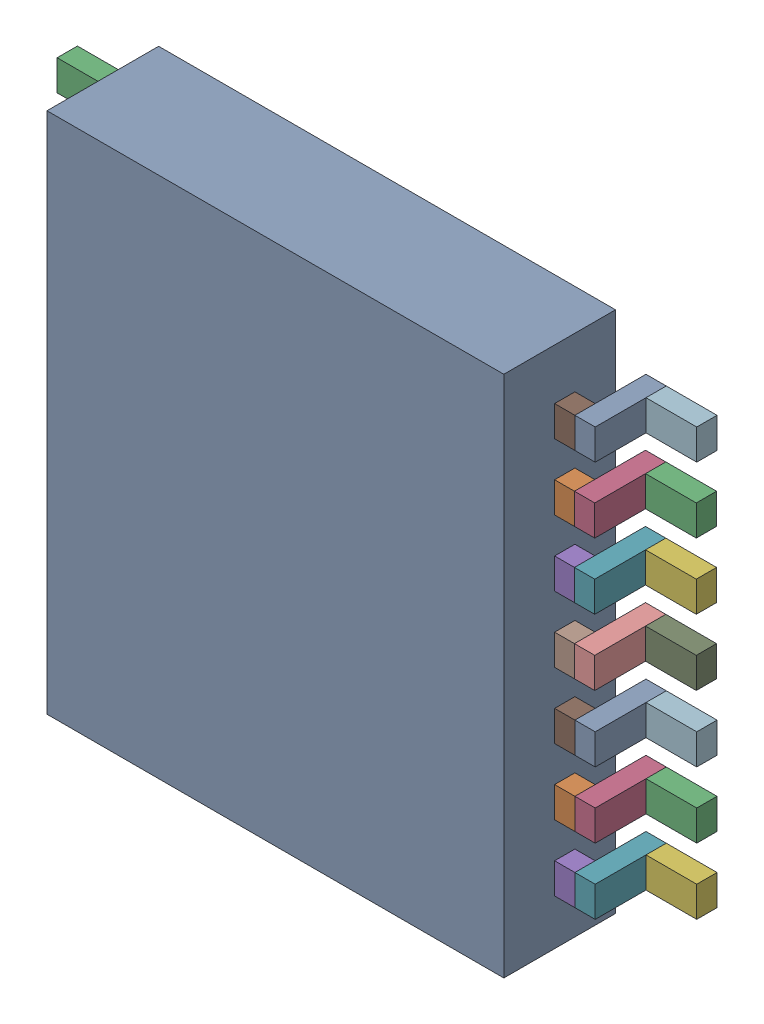
SolidWorks assembly U8, configuration Default. Lengths in mm.
Overall size (6.3 5.15 1.2).
86 component instances, 4 part files, 0 mates.
Components (placement in the parent):
- 859196720-1: 859196720 [Default] at (110.55 36.725 0.1) size (4.5 5.15 1.1)
  - Extruded_27-1: Extruded_27 [Default] at origin size (4.5 5.15 1.1)
- 836750064-1: 836750064 [Default] at (108 38.65 0) size (0.2 0.3 0.7)
  - Extruded_24-1: Extruded_24 [Default] at origin size (0.2 0.3 0.7)
- 836751344-1: 836751344 [Default] at (107.65 38.65 0) size (0.5 0.3 0.2)
  - Extruded_25-1: Extruded_25 [Default] at origin size (0.5 0.3 0.2)
- 836749808-1: 836749808 [Default] at (108.2 38.65 0.5) size (0.2 0.3 0.2)
  - Extruded_26-1: Extruded_26 [Default] at origin size (0.2 0.3 0.2)
- 836749808-2: 836749808 [Default] at (108.2 38 0.5) size (0.2 0.3 0.2)
  - Extruded_26-1: Extruded_26 [Default] at origin size (0.2 0.3 0.2)
- 836751344-2: 836751344 [Default] at (107.65 38 0) size (0.5 0.3 0.2)
  - Extruded_25-1: Extruded_25 [Default] at origin size (0.5 0.3 0.2)
- 836750064-2: 836750064 [Default] at (108 38 0) size (0.2 0.3 0.7)
  - Extruded_24-1: Extruded_24 [Default] at origin size (0.2 0.3 0.7)
- 836749808-3: 836749808 [Default] at (108.2 37.35 0.5) size (0.2 0.3 0.2)
  - Extruded_26-1: Extruded_26 [Default] at origin size (0.2 0.3 0.2)
- 836751344-3: 836751344 [Default] at (107.65 37.35 0) size (0.5 0.3 0.2)
  - Extruded_25-1: Extruded_25 [Default] at origin size (0.5 0.3 0.2)
- 836750064-3: 836750064 [Default] at (108 37.35 0) size (0.2 0.3 0.7)
  - Extruded_24-1: Extruded_24 [Default] at origin size (0.2 0.3 0.7)
- 836749808-4: 836749808 [Default] at (108.2 36.7 0.5) size (0.2 0.3 0.2)
  - Extruded_26-1: Extruded_26 [Default] at origin size (0.2 0.3 0.2)
- 836751344-4: 836751344 [Default] at (107.65 36.7 0) size (0.5 0.3 0.2)
  - Extruded_25-1: Extruded_25 [Default] at origin size (0.5 0.3 0.2)
- 836750064-4: 836750064 [Default] at (108 36.7 0) size (0.2 0.3 0.7)
  - Extruded_24-1: Extruded_24 [Default] at origin size (0.2 0.3 0.7)
- 836749808-5: 836749808 [Default] at (108.2 36.05 0.5) size (0.2 0.3 0.2)
  - Extruded_26-1: Extruded_26 [Default] at origin size (0.2 0.3 0.2)
- 836751344-5: 836751344 [Default] at (107.65 36.05 0) size (0.5 0.3 0.2)
  - Extruded_25-1: Extruded_25 [Default] at origin size (0.5 0.3 0.2)
- 836750064-5: 836750064 [Default] at (108 36.05 0) size (0.2 0.3 0.7)
  - Extruded_24-1: Extruded_24 [Default] at origin size (0.2 0.3 0.7)
- 836749808-6: 836749808 [Default] at (108.2 35.4 0.5) size (0.2 0.3 0.2)
  - Extruded_26-1: Extruded_26 [Default] at origin size (0.2 0.3 0.2)
- 836751344-6: 836751344 [Default] at (107.65 35.4 0) size (0.5 0.3 0.2)
  - Extruded_25-1: Extruded_25 [Default] at origin size (0.5 0.3 0.2)
- 836750064-6: 836750064 [Default] at (108 35.4 0) size (0.2 0.3 0.7)
  - Extruded_24-1: Extruded_24 [Default] at origin size (0.2 0.3 0.7)
- 836749808-7: 836749808 [Default] at (108.2 34.75 0.5) size (0.2 0.3 0.2)
  - Extruded_26-1: Extruded_26 [Default] at origin size (0.2 0.3 0.2)
- 836751344-7: 836751344 [Default] at (107.65 34.75 0) size (0.5 0.3 0.2)
  - Extruded_25-1: Extruded_25 [Default] at origin size (0.5 0.3 0.2)
- 836750064-7: 836750064 [Default] at (108 34.75 0) size (0.2 0.3 0.7)
  - Extruded_24-1: Extruded_24 [Default] at origin size (0.2 0.3 0.7)
- 836749808-8: 836749808 [Default] at (112.9 38.65 0.5) size (0.2 0.3 0.2)
  - Extruded_26-1: Extruded_26 [Default] at origin size (0.2 0.3 0.2)
- 836751344-8: 836751344 [Default] at (113.45 38.65 0) size (0.5 0.3 0.2)
  - Extruded_25-1: Extruded_25 [Default] at origin size (0.5 0.3 0.2)
- 836750064-8: 836750064 [Default] at (113.1 38.65 0) size (0.2 0.3 0.7)
  - Extruded_24-1: Extruded_24 [Default] at origin size (0.2 0.3 0.7)
- 836749808-9: 836749808 [Default] at (112.8954 38 0.5) size (0.2 0.3 0.2)
  - Extruded_26-1: Extruded_26 [Default] at origin size (0.2 0.3 0.2)
- 836751344-9: 836751344 [Default] at (113.4454 38 0) size (0.5 0.3 0.2)
  - Extruded_25-1: Extruded_25 [Default] at origin size (0.5 0.3 0.2)
- 836750064-9: 836750064 [Default] at (113.0954 38 0) size (0.2 0.3 0.7)
  - Extruded_24-1: Extruded_24 [Default] at origin size (0.2 0.3 0.7)
- 836749808-10: 836749808 [Default] at (112.8954 37.35 0.5) size (0.2 0.3 0.2)
  - Extruded_26-1: Extruded_26 [Default] at origin size (0.2 0.3 0.2)
- 836751344-10: 836751344 [Default] at (113.4454 37.35 0) size (0.5 0.3 0.2)
  - Extruded_25-1: Extruded_25 [Default] at origin size (0.5 0.3 0.2)
- 836750064-10: 836750064 [Default] at (113.0954 37.35 0) size (0.2 0.3 0.7)
  - Extruded_24-1: Extruded_24 [Default] at origin size (0.2 0.3 0.7)
- 836749808-11: 836749808 [Default] at (112.8954 36.7 0.5) size (0.2 0.3 0.2)
  - Extruded_26-1: Extruded_26 [Default] at origin size (0.2 0.3 0.2)
- 836751344-11: 836751344 [Default] at (113.4454 36.7 0) size (0.5 0.3 0.2)
  - Extruded_25-1: Extruded_25 [Default] at origin size (0.5 0.3 0.2)
- 836750064-11: 836750064 [Default] at (113.0954 36.7 0) size (0.2 0.3 0.7)
  - Extruded_24-1: Extruded_24 [Default] at origin size (0.2 0.3 0.7)
- 836749808-12: 836749808 [Default] at (112.9 36.05 0.5) size (0.2 0.3 0.2)
  - Extruded_26-1: Extruded_26 [Default] at origin size (0.2 0.3 0.2)
- 836751344-12: 836751344 [Default] at (113.45 36.05 0) size (0.5 0.3 0.2)
  - Extruded_25-1: Extruded_25 [Default] at origin size (0.5 0.3 0.2)
- 836750064-12: 836750064 [Default] at (113.1 36.05 0) size (0.2 0.3 0.7)
  - Extruded_24-1: Extruded_24 [Default] at origin size (0.2 0.3 0.7)
- 836749808-13: 836749808 [Default] at (112.9 35.4 0.5) size (0.2 0.3 0.2)
  - Extruded_26-1: Extruded_26 [Default] at origin size (0.2 0.3 0.2)
- 836751344-13: 836751344 [Default] at (113.45 35.4 0) size (0.5 0.3 0.2)
  - Extruded_25-1: Extruded_25 [Default] at origin size (0.5 0.3 0.2)
- 836750064-13: 836750064 [Default] at (113.1 35.4 0) size (0.2 0.3 0.7)
  - Extruded_24-1: Extruded_24 [Default] at origin size (0.2 0.3 0.7)
- 836749808-14: 836749808 [Default] at (112.9 34.75 0.5) size (0.2 0.3 0.2)
  - Extruded_26-1: Extruded_26 [Default] at origin size (0.2 0.3 0.2)
- 836751344-14: 836751344 [Default] at (113.45 34.75 0) size (0.5 0.3 0.2)
  - Extruded_25-1: Extruded_25 [Default] at origin size (0.5 0.3 0.2)
- 836750064-14: 836750064 [Default] at (113.1 34.75 0) size (0.2 0.3 0.7)
  - Extruded_24-1: Extruded_24 [Default] at origin size (0.2 0.3 0.7)
